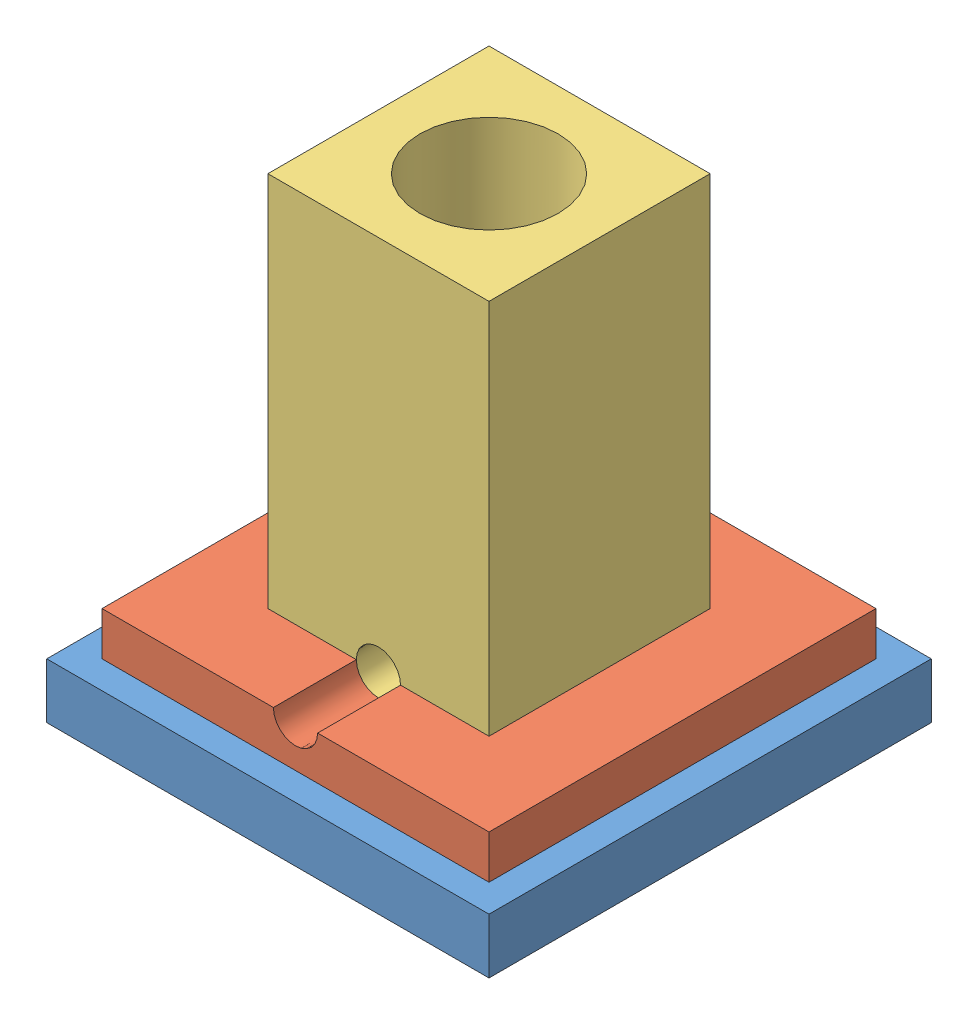
SolidWorks assembly lec42-assembly-features, configuration Default. Lengths in mm.
Overall size (101.6 109.22 101.6).
3 component instances, 3 part files, 4 mates.
Components (placement in the parent):
- Base-1: Base [Default] at (40.3068 38.3558 82.3784) size (101.6 12.7 101.6)
- Middle Block-1: Middle Block [Default] at (40.3068 51.0558 82.3784) size (88.9 10 88.9)
- Rod-1: Rod [Default] at (40.3068 45.9758 82.3784) size (50.8 101.6 50.8)
Mates (geometry in assembly coordinates):
- ProfileCenter1: profile center anti-aligned: plane of Base-1 through (40.3068 51.0558 82.3784) normal (0 1 0); plane of Middle Block-1 through (40.3068 51.0558 82.3784) normal (0 -1 0)
- Coincident1: coincident anti-aligned: plane of Base-1 through (40.3068 45.9758 82.3784) normal (0 1 0); plane of Rod-1 through (40.3068 45.9758 82.3784) normal (0 -1 0)
- Coincident2: coincident anti-aligned: plane of Middle Block-1 through (14.9068 51.0548 56.9784) normal (1 0 0); plane of Rod-1 through (14.9068 147.5758 56.9784) normal (-1 0 0)
- Coincident3: coincident anti-aligned: plane of Middle Block-1 through (65.7068 51.0548 56.9784) normal (0 0 1); plane of Rod-1 through (65.7068 147.5758 56.9784) normal (0 0 -1)
